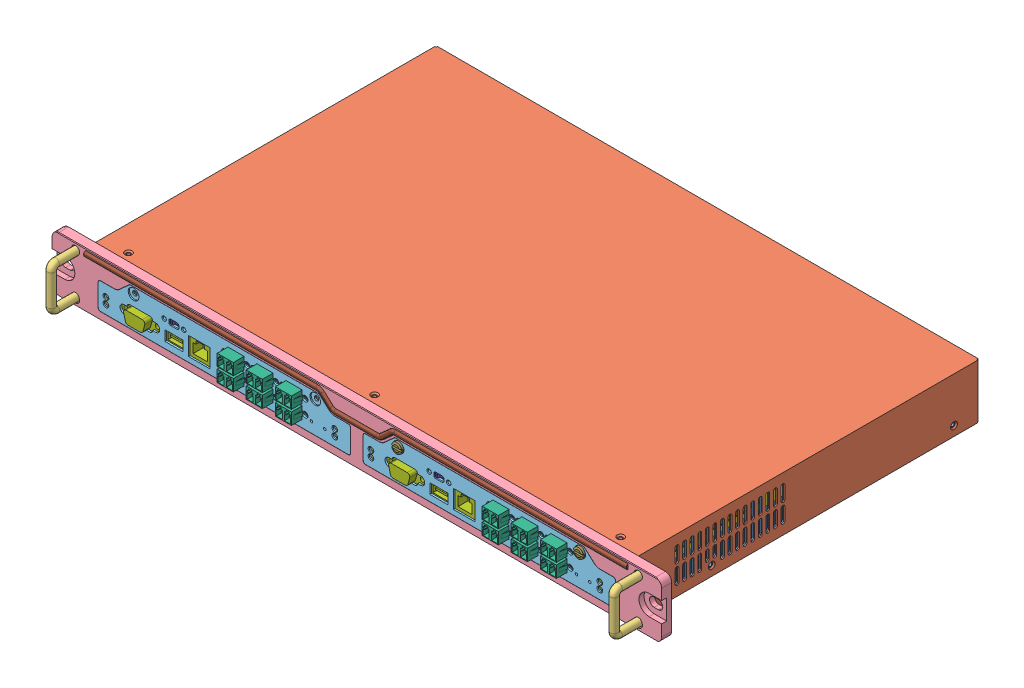
SolidWorks assembly User Library-fod-assy_asm, configuration Default. Lengths in mm.
Overall size (483 43.5 300.15).
40 component instances, 15 part files, 0 mates.
Components (placement in the parent):
- User Library-fod-assy_asm_FOD-BASE-1: User Library-fod-assy_asm_FOD-BASE [Default] at origin size (428 42.5 268.8)
- User Library-fod-assy_asm_FOD-TOP-COVER-1: User Library-fod-assy_asm_FOD-TOP-COVER [Default] at (0 43.5 -17) size (430.4 43 270)
- User Library-fod-assy_asm_PRT0002-1: User Library-fod-assy_asm_PRT0002 [Default] at (223 22 5) x (1 0 0) z (0 -1 0) size (6 25.15 37.6)
- User Library-fod-assy_asm_PRT0002-2: User Library-fod-assy_asm_PRT0002 [Default] at (-223 22 5) x (-1 0 0) z (0 1 0) size (6 25.15 37.6)
- User Library-fod-assy_asm_FOD-FRONT-PANEL-1: User Library-fod-assy_asm_FOD-FRONT-PANEL [Default] at (0 22 0) size (483 43.5 17)
- User Library-fod-assy_asm_FOD-MODULE-ASSY_ASM-1: User Library-fod-assy_asm_FOD-MODULE-ASSY_ASM [Default] at (-205 9 5) size (200 30 265.8)
  - User Library-fod-assy_asm_FOD-IO-PANEL-1: User Library-fod-assy_asm_FOD-IO-PANEL [Default] at (0 -2.9 1) size (200 30 14)
  - User Library-fod-assy_asm_CONN-LC-TYPE-SCREW-1: User Library-fod-assy_asm_CONN-LC-TYPE-SCREW [Default] at (109 12 11.3) x (-1 0 0) z (0 0 1) size (22 9.3 25.8)
  - User Library-fod-assy_asm_CONN-LC-TYPE-SCREW-2: User Library-fod-assy_asm_CONN-LC-TYPE-SCREW [Default] at (132 12 11.3) x (-1 0 0) z (0 0 1) size (22 9.3 25.8)
  - User Library-fod-assy_asm_CONN-LC-TYPE-SCREW-3: User Library-fod-assy_asm_CONN-LC-TYPE-SCREW [Default] at (155 12 11.3) x (-1 0 0) z (0 0 1) size (22 9.3 25.8)
  - User Library-fod-assy_asm_CONN-LC-TYPE-SCREW-4: User Library-fod-assy_asm_CONN-LC-TYPE-SCREW [Default] at (109 23 11.3) x (-1 0 0) z (0 0 1) size (22 9.3 25.8)
  - User Library-fod-assy_asm_CONN-LC-TYPE-SCREW-5: User Library-fod-assy_asm_CONN-LC-TYPE-SCREW [Default] at (132 23 11.3) x (-1 0 0) z (0 0 1) size (22 9.3 25.8)
  - User Library-fod-assy_asm_CONN-LC-TYPE-SCREW-6: User Library-fod-assy_asm_CONN-LC-TYPE-SCREW [Default] at (155 23 11.3) x (-1 0 0) z (0 0 1) size (22 9.3 25.8)
  - User Library-fod-assy_asm_FOD-MAIN-BD-1: User Library-fod-assy_asm_FOD-MAIN-BD [Default] at origin size (200 15.1 262)
  - User Library-fod-assy_asm_SLIDE-SWITCH-1: User Library-fod-assy_asm_SLIDE-SWITCH [Default] at (60 14.5 -5) size (19 6 10.5)
  - User Library-fod-assy_asm_FOD-BD-COVER-1: User Library-fod-assy_asm_FOD-BD-COVER [Default] at (100 7.6 -120) size (190 9 90)
- User Library-fod-assy_asm_FOD-MODULE-ASSY_ASM-2: User Library-fod-assy_asm_FOD-MODULE-ASSY_ASM [Default] at (5 9 5) size (200 30 265.8)
  - User Library-fod-assy_asm_FOD-IO-PANEL-1: User Library-fod-assy_asm_FOD-IO-PANEL [Default] at (0 -2.9 1) size (200 30 14)
  - User Library-fod-assy_asm_CONN-LC-TYPE-SCREW-1: User Library-fod-assy_asm_CONN-LC-TYPE-SCREW [Default] at (109 12 11.3) x (-1 0 0) z (0 0 1) size (22 9.3 25.8)
  - User Library-fod-assy_asm_CONN-LC-TYPE-SCREW-2: User Library-fod-assy_asm_CONN-LC-TYPE-SCREW [Default] at (132 12 11.3) x (-1 0 0) z (0 0 1) size (22 9.3 25.8)
  - User Library-fod-assy_asm_CONN-LC-TYPE-SCREW-3: User Library-fod-assy_asm_CONN-LC-TYPE-SCREW [Default] at (155 12 11.3) x (-1 0 0) z (0 0 1) size (22 9.3 25.8)
  - User Library-fod-assy_asm_CONN-LC-TYPE-SCREW-4: User Library-fod-assy_asm_CONN-LC-TYPE-SCREW [Default] at (109 23 11.3) x (-1 0 0) z (0 0 1) size (22 9.3 25.8)
  - User Library-fod-assy_asm_CONN-LC-TYPE-SCREW-5: User Library-fod-assy_asm_CONN-LC-TYPE-SCREW [Default] at (132 23 11.3) x (-1 0 0) z (0 0 1) size (22 9.3 25.8)
  - User Library-fod-assy_asm_CONN-LC-TYPE-SCREW-6: User Library-fod-assy_asm_CONN-LC-TYPE-SCREW [Default] at (155 23 11.3) x (-1 0 0) z (0 0 1) size (22 9.3 25.8)
  - User Library-fod-assy_asm_FOD-MAIN-BD-1: User Library-fod-assy_asm_FOD-MAIN-BD [Default] at origin size (200 15.1 262)
  - User Library-fod-assy_asm_SLIDE-SWITCH-1: User Library-fod-assy_asm_SLIDE-SWITCH [Default] at (60 14.5 -5) size (19 6 10.5)
  - User Library-fod-assy_asm_FOD-BD-COVER-1: User Library-fod-assy_asm_FOD-BD-COVER [Default] at (100 7.6 -120) size (190 9 90)
- User Library-fod-assy_asm_FOD-PCB-GUIDE-1: User Library-fod-assy_asm_FOD-PCB-GUIDE [Default] at (-202.7 1 -5) size (7 14 235)
- User Library-fod-assy_asm_FOD-PCB-GUIDE-2: User Library-fod-assy_asm_FOD-PCB-GUIDE [Default] at (7.3 1 -5) size (7 14 235)
- User Library-fod-assy_asm_FOD-PCB-GUIDE-3: User Library-fod-assy_asm_FOD-PCB-GUIDE [Default] at (-7.3 1 -250) x (-1 0 0) z (0 0 -1) size (7 14 235)
- User Library-fod-assy_asm_FOD-PCB-GUIDE-4: User Library-fod-assy_asm_FOD-PCB-GUIDE [Default] at (202.7 1 -250) x (-1 0 0) z (0 0 -1) size (7 14 235)
- User Library-fod-assy_asm_FOD-DESIGN-BAR-1: User Library-fod-assy_asm_FOD-DESIGN-BAR [Default] at (0 41.9 6) size (430 13.1 3.5)
- User Library-fod-assy_asm_FOD-CAP-SCREW-1: User Library-fod-assy_asm_FOD-CAP-SCREW [Default] at (177 31.1 7) size (8 8 15)
- User Library-fod-assy_asm_FOD-CAP-SCREW-2: User Library-fod-assy_asm_FOD-CAP-SCREW [Default] at (33 31.1 7) size (8 8 15)
- User Library-fod-assy_asm_FOD-FRONT-BRKT-1: User Library-fod-assy_asm_FOD-FRONT-BRKT [Default] at (0 38.7 0) size (370 13 11)
- User Library-fod-assy_asm_FOD-SIDE-BRKT-1: User Library-fod-assy_asm_FOD-SIDE-BRKT [Default] at (213 37 0) x (-1 0 0) z (0 0 1) size (7.8 31 12)
- User Library-fod-assy_asm_FOD-SIDE-BRKT-2: User Library-fod-assy_asm_FOD-SIDE-BRKT [Default] at (-213 6 0) size (7.8 31 12)
- User Library-fod-assy_asm_FOD-BP-BD-ST-1: User Library-fod-assy_asm_FOD-BP-BD-ST [Default] at (-5 9 -254.8) x (1 0 0) z (0 -1 0) size (270 24.5 30)
- User Library-fod-assy_asm_SLIDE-SWITCH-1: User Library-fod-assy_asm_SLIDE-SWITCH [Default] at (177 25 -261.8) x (1 0 0) z (0 0 -1) size (19 6 10.5)
- User Library-fod-assy_asm_SLIDE-SWITCH-2: User Library-fod-assy_asm_SLIDE-SWITCH [Default] at (-177 19 -261.8) x (-1 0 0) z (0 0 -1) size (19 6 10.5)
